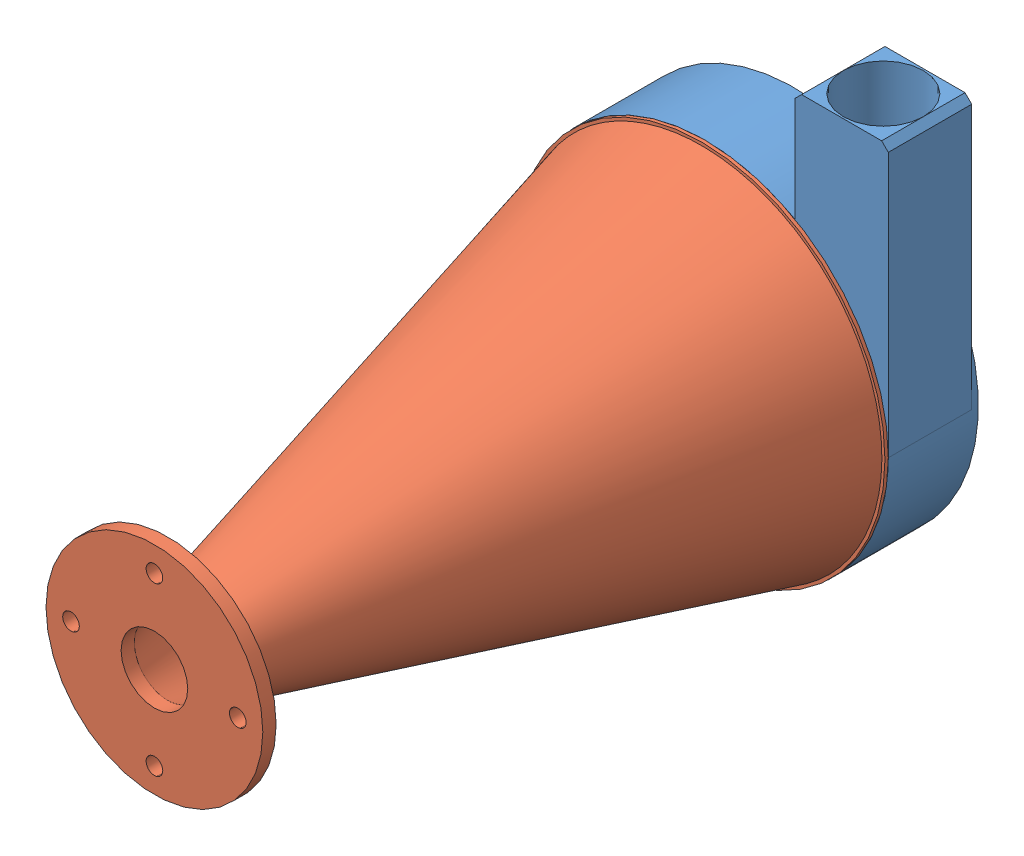
SolidWorks assembly montagem_ciclone, configuration Default. Lengths in mm.
Overall size (115.72 137.79 192).
2 component instances, 2 part files, 2 mates.
Components (placement in the parent):
- tampa-1: tampa [Default] at (26.6103 106.1585 123.9507) size (113 137.79 52)
- cone-3: cone [Default] at (26.6103 106.1585 148.9507) size (115.72 112.27 165)
Mates (geometry in assembly coordinates):
- Coincident5: coincident anti-aligned: plane of tampa-1 through (26.6103 106.1585 148.9507) normal (0 0 1); plane of cone-3 through (26.6103 106.1585 148.9507) normal (0 0 -1)
- Concentric2: concentric anti-aligned: cylinder of tampa-1 through (26.6103 106.1585 148.9507) axis (0 0 -1) radius 52; circle of cone-3
